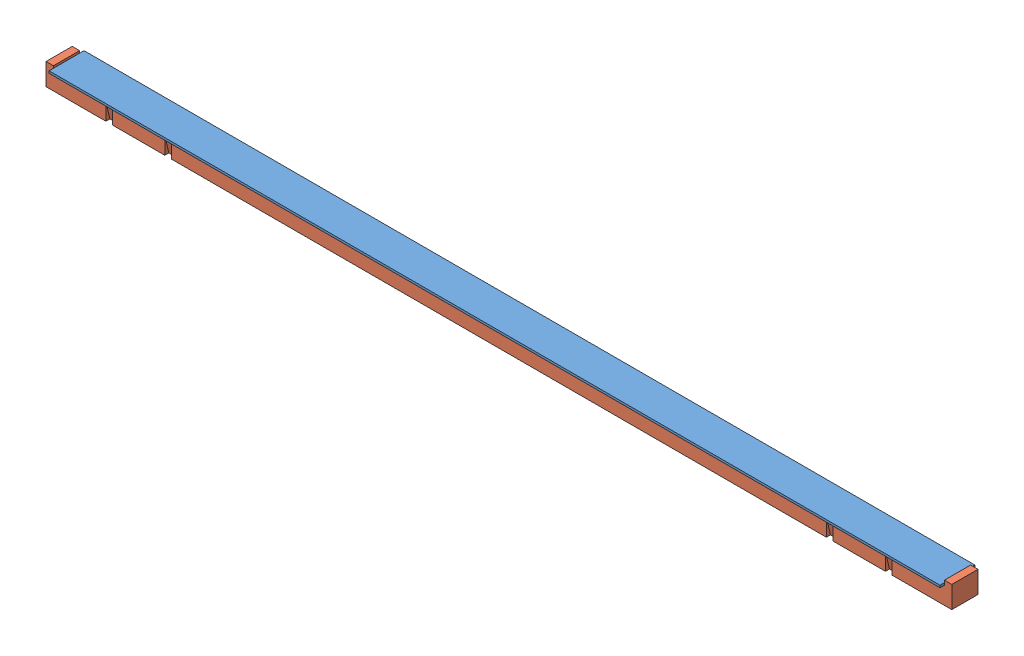
SolidWorks assembly FLOOR GAP ASSEMPLY, configuration Default. Lengths in mm.
Overall size (2633.98 63.5 101.6).
2 component instances, 2 part files, 2 mates.
Components (placement in the parent):
- FLOOR GAP WOOD-1: FLOOR GAP WOOD [Default] at (1058.7388 1420.6403 1891.5157) size (2590.8 6.35 101.6)
- FLOOR GAP INSULATION-1: FLOOR GAP INSULATION [Default] at (1058.7388 1369.8403 1891.5157) size (2633.98 63.5 76.2)
Mates (geometry in assembly coordinates):
- Coincident1: coincident: plane of FLOOR GAP WOOD-1 through (1058.7388 1420.6403 1891.5157) normal (0 -1 0); plane of FLOOR GAP INSULATION-1 through (1043.5388 1420.6403 1670.1728) normal (0 1 0)
- Coincident3: coincident: moEndPointRef_w of FLOOR GAP WOOD-1; moEndPointRef_w of FLOOR GAP INSULATION-1
